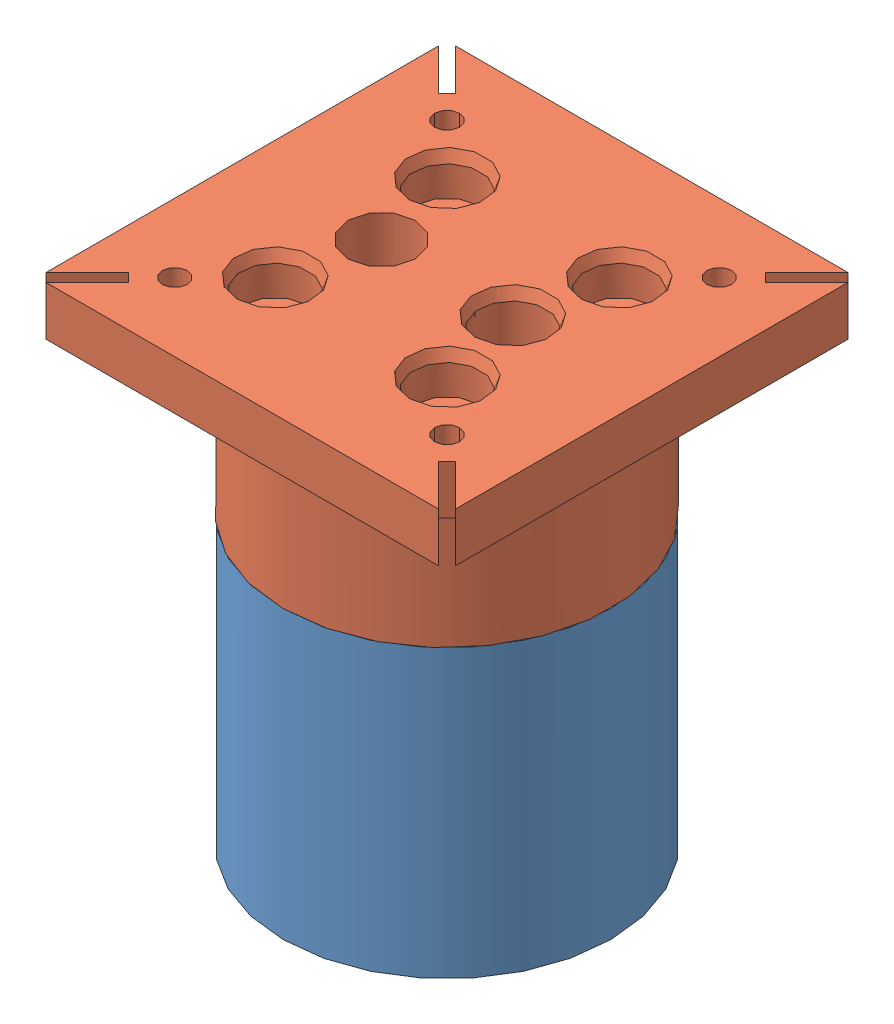
SolidWorks assembly Assem1, configuration По умолчанию. Lengths in mm.
Overall size (50 60 50).
2 component instances, 2 part files, 3 mates.
Components (placement in the parent):
- gimbal_stick_connector_p3_gimbal10-1: gimbal_stick_connector_p3_gimbal10 [По умолчанию] at origin size (40 35 40)
- gimbal_stick_connector_p4_gimbal11-1: gimbal_stick_connector_p4_gimbal11 [По умолчанию] at (0 35 0) size (50 30 50)
Mates (geometry in assembly coordinates):
- Concentric1: concentric: cylinder of gimbal_stick_connector_p3_gimbal10-1 through (0 35 0) axis (0 -1 0) radius 20; cylinder of gimbal_stick_connector_p4_gimbal11-1 through (0 107.0064 0) axis (0 -1 0) radius 20
- Concentric2: concentric: cylinder of gimbal_stick_connector_p3_gimbal10-1 through (-8 0 0) axis (0 1 0) radius 4.1; cylinder of gimbal_stick_connector_p4_gimbal11-1 through (-8 77.0064 0) axis (0 1 0) radius 4.1
- Coincident1: coincident anti-aligned: plane of gimbal_stick_connector_p3_gimbal10-1 through (0 35 0) normal (0 1 0); plane of gimbal_stick_connector_p4_gimbal11-1 through (0 35 0) normal (0 -1 0)
